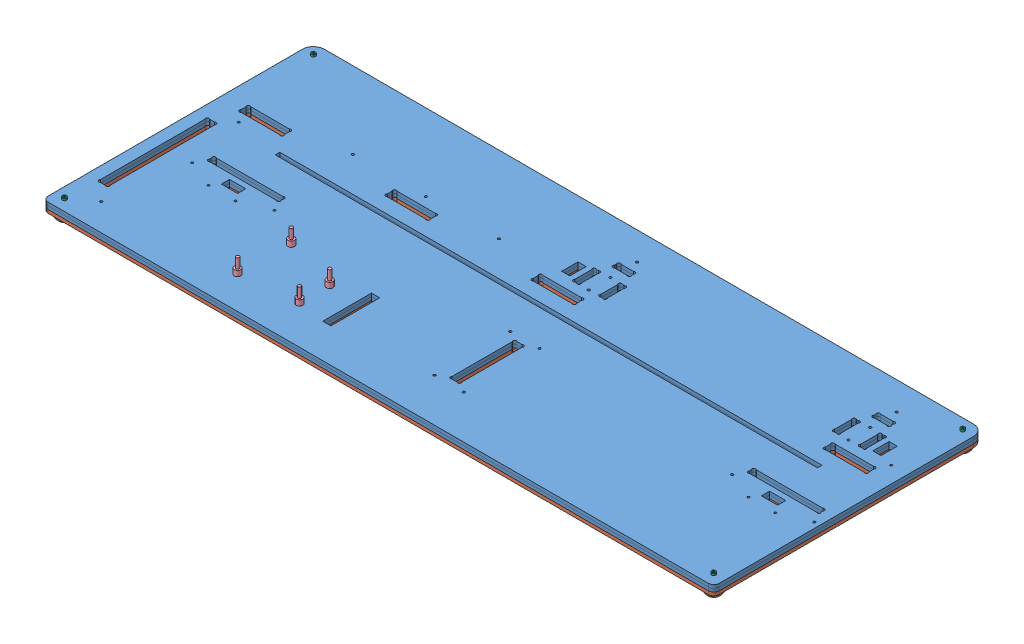
SolidWorks assembly socle-complet, configuration Défaut. Lengths in mm.
Overall size (621.62 30.7 251.62).
21 component instances, 6 part files, 49 mates.
Components (placement in the parent):
- socle-1-1: socle-1 [Défaut] at (-302.5453 40.1785 745) size (620 3 250)
- socle-1-2: socle-1 [Défaut] at (-302.5453 37.1785 745) size (620 3 250)
- socle-2-3: socle-2 [Défaut] at (-302.5453 34.1785 745) size (620 3 250)
- socle-patin-ecrou_m2-1: socle-patin-ecrou_m2 [Défaut] at (-292.5453 34.1785 735) x (0.367083 0 0.930188) z (-0.930188 0 0.367083) size (16 7.7 16)
- socle-patin-ecrou_m2-2: socle-patin-ecrou_m2 [Défaut] at (-292.5453 34.1785 505) x (-0.622025 0 0.782997) z (-0.782997 0 -0.622025) size (16 7.7 16)
- socle-patin-ecrou_m2-3: socle-patin-ecrou_m2 [Défaut] at (307.4547 34.1785 505) x (0.367083 0 0.930188) z (-0.930188 0 0.367083) size (16 7.7 16)
- socle-patin-ecrou_m2-4: socle-patin-ecrou_m2 [Défaut] at (307.4547 34.1785 735) x (0.367083 0 0.930188) z (-0.930188 0 0.367083) size (16 7.7 16)
- socle-carte_pied-1: socle-carte_pied [Défaut] at (-152.5453 38.1785 715) x (0 1 0) z (-0.920347 0 -0.391102) size (19 6 6)
- socle-carte_pied-2: socle-carte_pied [Défaut] at (-151.2753 38.1785 666.74) x (0 1 0) z (-0.842592 0 -0.538553) size (19 6 6)
- socle-carte_pied-3: socle-carte_pied [Défaut] at (-100.4753 38.1785 681.98) x (0 1 0) z (-0.819102 0 -0.573647) size (19 6 6)
- socle-carte_pied-4: socle-carte_pied [Défaut] at (-100.4753 38.1785 709.92) x (0 1 0) z (0.984574 0 0.174968) size (19 6 6)
- ecrou-h-1: ecrou-h [6007 HU M2] at (-292.5453 31.1785 735) size (4 1.6 4.62)
- vis-chc-1: vis-chc [Vis CHC M2x16] at (-292.5453 43.1785 735) x (0.999999 0 -0.001395) z (0.001395 0 0.999999) size (3.8 18 3.8)
- vis-chc-2: vis-chc [Vis CHC M2x16] at (307.4547 43.1785 735) x (0.999999 0 -0.001395) z (0.001395 0 0.999999) size (3.8 18 3.8)
- vis-chc-3: vis-chc [Vis CHC M2x16] at (-292.5453 43.1785 505) x (0.610012 0 -0.792392) z (0.792392 0 0.610012) size (3.8 18 3.8)
- vis-chc-4: vis-chc [Vis CHC M2x16] at (307.4547 43.1785 505) x (0.999999 0 -0.001395) z (0.001395 0 0.999999) size (3.8 18 3.8)
- ecrou-h-2: ecrou-h [6007 HU M2] at (307.4547 31.1785 735) size (4 1.6 4.62)
- ecrou-h-3: ecrou-h [6007 HU M2] at (307.4547 31.1785 505) size (4 1.6 4.62)
- ecrou-h-4: ecrou-h [6007 HU M2] at (-292.5453 31.1785 505) size (4 1.6 4.62)
- socle-patin-ecrou_m2-5: socle-patin-ecrou_m2 [Défaut] at (22.4547 34.1785 521) x (-0.256954 0 0.966424) z (-0.966424 0 -0.256954) size (16 7.7 16)
- socle-patin-ecrou_m2-6: socle-patin-ecrou_m2 [Défaut] at (19.4547 34.1785 705) x (0.367083 0 0.930188) z (-0.930188 0 0.367083) size (16 7.7 16)
Mates (geometry in assembly coordinates):
- Coïncidente1: coincident anti-aligned: plane of socle-1-1 through (-292.5453 40.1785 505) normal (0 -1 0); plane of socle-1-2 through (-292.5453 40.1785 505) normal (0 1 0)
- Coïncidente2: coincident aligned: plane of socle-1-1 through (-302.5453 43.1785 745) normal (0 0 1); plane of socle-1-2 through (-302.5453 40.1785 745) normal (0 0 1)
- Coïncidente3: coincident aligned: plane of socle-1-1 through (-302.5453 43.1785 505) normal (-1 0 0); plane of socle-1-2 through (-302.5453 40.1785 505) normal (-1 0 0)
- Coïncidente4: coincident anti-aligned: plane of socle-1-2 through (-292.5453 37.1785 505) normal (0 -1 0); plane of socle-3 through (-292.5453 37.1785 505) normal (0 1 0)
- Coïncidente5: coincident aligned: plane of socle-1-2 through (-302.5453 40.1785 745) normal (0 0 1); plane of socle-3 through (-302.5453 37.1785 745) normal (0 0 1)
- Coïncidente6: coincident aligned: plane of socle-1-2 through (-302.5453 40.1785 505) normal (-1 0 0); plane of socle-3 through (-302.5453 37.1785 505) normal (-1 0 0)
- Coaxiale1: concentric anti-aligned: cylinder of socle-3 through (-292.5453 37.1785 735) axis (0 -1 0) radius 1.1; cylinder of socle-patin-ecrou_m2-1 through (-292.5453 26.1785 735) axis (0 1 0) radius 1.1
- Coïncidente7: coincident anti-aligned: plane of socle-3 through (-292.5453 34.1785 505) normal (0 -1 0); plane of socle-patin-ecrou_m2-1 through (-295.482 34.1785 727.5585) normal (0 1 0)
- Coaxiale2: concentric anti-aligned: cylinder of socle-3 through (307.4547 37.1785 735) axis (0 -1 0) radius 1.1; cylinder of socle-patin-ecrou_m2-4 through (307.4547 26.1785 735) axis (0 1 0) radius 1.1
- Coaxiale3: concentric anti-aligned: cylinder of socle-3 through (307.4547 37.1785 505) axis (0 -1 0) radius 1.1; cylinder of socle-patin-ecrou_m2-3 through (307.4547 26.1785 505) axis (0 1 0) radius 1.1
- Coaxiale4: concentric anti-aligned: cylinder of socle-3 through (-292.5453 37.1785 505) axis (0 -1 0) radius 1.1; cylinder of socle-patin-ecrou_m2-2 through (-292.5453 26.1785 505) axis (0 1 0) radius 1.1
- Coïncidente8: coincident anti-aligned: plane of socle-3 through (-292.5453 34.1785 505) normal (0 -1 0); plane of socle-patin-ecrou_m2-2 through (-287.5691 34.1785 498.736) normal (0 1 0)
- Coïncidente9: coincident anti-aligned: plane of socle-3 through (-292.5453 34.1785 505) normal (0 -1 0); plane of socle-patin-ecrou_m2-3 through (304.518 34.1785 497.5585) normal (0 1 0)
- Coïncidente10: coincident anti-aligned: plane of socle-3 through (-292.5453 34.1785 505) normal (0 -1 0); plane of socle-patin-ecrou_m2-4 through (304.518 34.1785 727.5585) normal (0 1 0)
- Parallèle1: parallel anti-aligned: plane of socle-3 through (317.4547 37.1785 505) normal (1 0 0); plane of socle-patin-ecrou_m2-4 through (309.6198 26.2545 736.25) normal (-1 0 0)
- Parallèle2: parallel anti-aligned: plane of socle-3 through (317.4547 37.1785 505) normal (1 0 0); plane of socle-patin-ecrou_m2-3 through (309.6198 26.2545 506.25) normal (-1 0 0)
- Parallèle3: parallel anti-aligned: plane of socle-3 through (-302.5453 37.1785 505) normal (-1 0 0); plane of socle-patin-ecrou_m2-1 through (-294.7104 26.2545 733.75) normal (1 0 0)
- Parallèle4: parallel anti-aligned: plane of socle-3 through (-302.5453 37.1785 505) normal (-1 0 0); plane of socle-patin-ecrou_m2-2 through (-294.7104 26.2545 503.75) normal (1 0 0)
- Coaxiale5: concentric aligned: cylinder of socle-1-1 through (-152.5453 40.1785 715) axis (0 1 0) radius 1.59; cylinder of socle-carte_pied-1 through (-152.5453 57.1785 715) axis (0 1 0) radius 1.5
- Coaxiale6: concentric aligned: cylinder of socle-1-1 through (-100.4753 40.1785 709.92) axis (0 1 0) radius 1.59; cylinder of socle-carte_pied-4 through (-100.4753 57.1785 709.92) axis (0 1 0) radius 1.5
- Coaxiale7: concentric aligned: cylinder of socle-1-1 through (-100.4753 40.1785 681.98) axis (0 1 0) radius 1.59; cylinder of socle-carte_pied-3 through (-100.4753 57.1785 681.98) axis (0 1 0) radius 1.5
- Coaxiale8: concentric aligned: cylinder of socle-1-1 through (-151.2753 40.1785 666.74) axis (0 1 0) radius 1.59; cylinder of socle-carte_pied-2 through (-151.2753 57.1785 666.74) axis (0 1 0) radius 1.5
- Coïncidente11: coincident anti-aligned: plane of socle-1-1 through (-292.5453 43.1785 505) normal (0 1 0); plane of socle-carte_pied-1 through (-151.9586 43.1785 713.6195) normal (0 -1 0)
- Coïncidente12: coincident anti-aligned: plane of socle-1-1 through (-292.5453 43.1785 505) normal (0 1 0); plane of socle-carte_pied-2 through (-150.4675 43.1785 665.4761) normal (0 -1 0)
- Coïncidente13: coincident anti-aligned: plane of socle-1-1 through (-292.5453 43.1785 505) normal (0 1 0); plane of socle-carte_pied-3 through (-99.6148 43.1785 680.7513) normal (0 -1 0)
- Coïncidente14: coincident anti-aligned: plane of socle-1-1 through (-292.5453 43.1785 505) normal (0 1 0); plane of socle-carte_pied-4 through (-100.7378 43.1785 711.3969) normal (0 -1 0)
- Coaxiale9: concentric anti-aligned: cylinder of socle-1-1 through (-292.5453 43.1785 735) axis (0 -1 0) radius 1.1; cylinder of vis-chc-1 through (-292.5453 27.1785 735) axis (0 1 0) radius 1
- Coïncidente15: coincident anti-aligned: plane of socle-1-1 through (-292.5453 43.1785 505) normal (0 1 0); plane of vis-chc-1 through (-292.5453 43.1785 735) normal (0 -1 0)
- Coaxiale10: concentric aligned: cylinder of ecrou-h-1 through (-292.5453 29.5785 735) axis (0 1 0) radius 0.7835; cylinder of vis-chc-1 through (-292.5453 27.1785 735) axis (0 1 0) radius 1
- Parallèle5: parallel anti-aligned: plane of socle-patin-ecrou_m2-1 through (-292.5453 26.2545 732.5) normal (0.5 0 0.866025); plane of ecrou-h-1 through (-292.5453 29.5785 732.6906) normal (-0.5 0 -0.866025)
- Coïncidente18: coincident anti-aligned: plane of socle-patin-ecrou_m2-1 through (-292.5453 31.1785 735) normal (0 -1 0); plane of ecrou-h-1 through (-290.5453 31.1785 733.8453) normal (0 1 0)
- Coaxiale11: concentric anti-aligned: cylinder of socle-1-1 through (307.4547 43.1785 735) axis (0 -1 0) radius 1.1; cylinder of vis-chc-2 through (307.4547 27.1785 735) axis (0 1 0) radius 1
- Coïncidente19: coincident aligned: plane of socle-1-1 through (-292.5453 43.1785 505) normal (0 1 0); circle of vis-chc-2
- Coaxiale12: concentric anti-aligned: cylinder of socle-1-1 through (307.4547 43.1785 505) axis (0 -1 0) radius 1.1; cylinder of vis-chc-4 through (307.4547 27.1785 505) axis (0 1 0) radius 1
- Coïncidente20: coincident anti-aligned: plane of socle-1-1 through (-292.5453 43.1785 505) normal (0 1 0); plane of vis-chc-4 through (307.4547 43.1785 505) normal (0 -1 0)
- Coaxiale13: concentric anti-aligned: cylinder of socle-1-1 through (-292.5453 43.1785 505) axis (0 -1 0) radius 1.1; cylinder of vis-chc-3 through (-292.5453 27.1785 505) axis (0 1 0) radius 1
- Coïncidente21: coincident anti-aligned: plane of socle-1-1 through (-292.5453 43.1785 505) normal (0 1 0); plane of vis-chc-3 through (-292.5453 43.1785 505) normal (0 -1 0)
- Coïncidente22: coincident anti-aligned: plane of socle-patin-ecrou_m2-2 through (-292.5453 31.1785 505) normal (0 -1 0); plane of ecrou-h-4 through (-290.5453 31.1785 503.8453) normal (0 1 0)
- Parallèle10: parallel anti-aligned: plane of socle-patin-ecrou_m2-2 through (-294.7104 26.2545 506.25) normal (0.5 0 -0.866025); plane of ecrou-h-4 through (-294.5453 29.5785 506.1547) normal (-0.5 0 0.866025)
- Coaxiale20: concentric aligned: cylinder of vis-chc-3 through (-292.5453 27.1785 505) axis (0 1 0) radius 1; cylinder of ecrou-h-4 through (-292.5453 29.5785 505) axis (0 1 0) radius 0.7835
- Coïncidente28: coincident anti-aligned: plane of socle-patin-ecrou_m2-3 through (307.4547 31.1785 505) normal (0 -1 0); plane of ecrou-h-3 through (309.4547 31.1785 503.8453) normal (0 1 0)
- Parallèle11: parallel anti-aligned: plane of socle-patin-ecrou_m2-3 through (305.2896 26.2545 506.25) normal (0.5 0 -0.866025); plane of ecrou-h-3 through (305.4547 29.5785 506.1547) normal (-0.5 0 0.866025)
- Coaxiale21: concentric aligned: cylinder of vis-chc-4 through (307.4547 27.1785 505) axis (0 1 0) radius 1; cylinder of ecrou-h-3 through (307.4547 29.5785 505) axis (0 1 0) radius 0.7835
- Coïncidente30: coincident anti-aligned: plane of socle-patin-ecrou_m2-4 through (307.4547 31.1785 735) normal (0 -1 0); plane of ecrou-h-2 through (309.4547 31.1785 733.8453) normal (0 1 0)
- Parallèle13: parallel anti-aligned: plane of socle-patin-ecrou_m2-4 through (307.4547 26.2545 737.5) normal (-0.5 0 -0.866025); plane of ecrou-h-2 through (307.4547 29.5785 737.3094) normal (0.5 0 0.866025)
- Coaxiale23: concentric aligned: cylinder of vis-chc-2 through (307.4547 27.1785 735) axis (0 1 0) radius 1; cylinder of ecrou-h-2 through (307.4547 29.5785 735) axis (0 1 0) radius 0.7835
- Coaxiale24: concentric aligned: cylinder of socle-2-3 through (22.4547 34.1785 521) axis (0 1 0) radius 1.1; cylinder of socle-patin-ecrou_m2-5 through (22.4547 26.1785 521) axis (0 1 0) radius 1.1
- Coaxiale25: concentric aligned: cylinder of socle-2-3 through (19.4547 34.1785 705) axis (0 1 0) radius 1.1; cylinder of socle-patin-ecrou_m2-6 through (19.4547 26.1785 705) axis (0 1 0) radius 1.1
- Coïncidente31: coincident anti-aligned: plane of socle-2-3 through (-292.5453 34.1785 505) normal (0 -1 0); plane of socle-patin-ecrou_m2-5 through (24.5103 34.1785 513.2686) normal (0 1 0)
